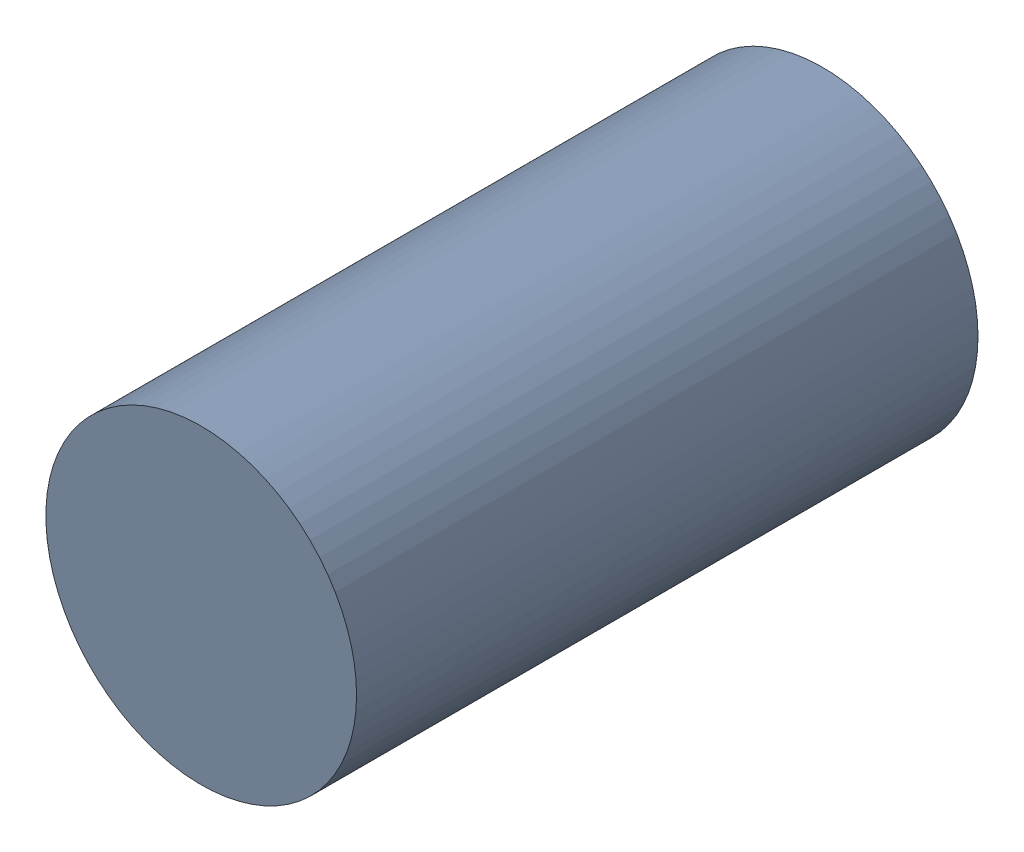
SolidWorks assembly MH11_2.step, configuration Default. Lengths in mm.
Overall size (1 1 2).
2 component instances, 1 part files, 0 mates.
Components (placement in the parent):
- 9228463120_2.step-2: 9228463120_2.step [Default] at (106.498 92.1997 -1.5) size (1 1 2)
  - Cylinder_4.step-7: Cylinder_4.step [Default] at origin size (1 1 2)
